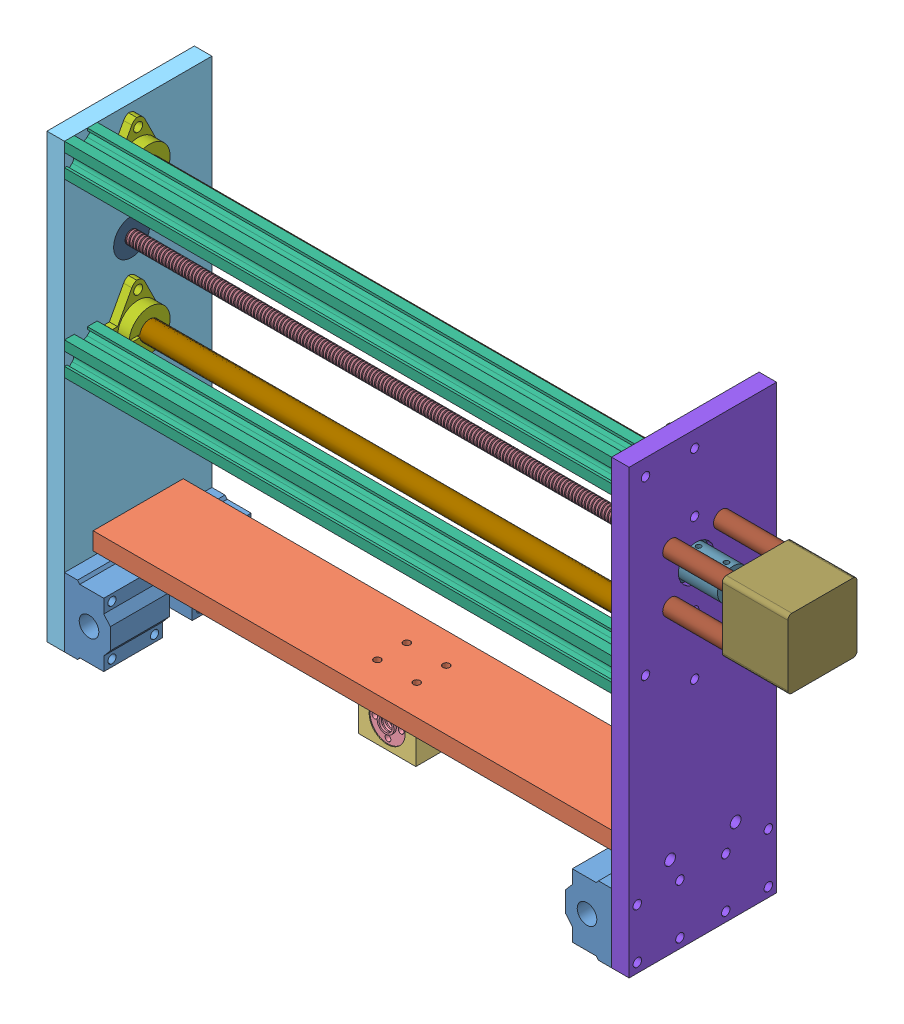
SolidWorks assembly MaquinaEixoX, configuration Valor predeterminado. Lengths in mm.
Overall size (432.4 270 90).
26 component instances, 14 part files, 65 mates.
Components (placement in the parent):
- PillowBlockSCS12UU_12mm-1: PillowBlockSCS12UU_12mm [Valor predeterminado] at (166.1121 14.2573 262.986) x (0 -1 0) z (0 0 1) size (42 28 36)
- PillowBlockSCS12UU_12mm-2: PillowBlockSCS12UU_12mm [Valor predeterminado] at (166.1121 14.2573 352.986) x (0 1 0) z (0 0 -1) size (42 28 36)
- PillowBlockSCS12UU_12mm-3: PillowBlockSCS12UU_12mm [Valor predeterminado] at (-123.9122 14.2573 316.986) x (0 1 0) z (0 0 1) size (42 28 36)
- PillowBlockSCS12UU_12mm-4: PillowBlockSCS12UU_12mm [Valor predeterminado] at (-123.9122 14.2573 262.986) x (0 1 0) z (0 0 1) size (42 28 36)
- EixoYChapaBase-1: EixoYChapaBase [Valor predeterminado] at (188.0999 43.2573 307.986) x (0 0 1) z (-1 0 0) size (55 10.7 334)
- SuporteCastanhaTr8-1: SuporteCastanhaTr8 [Valor predeterminado] at (21.0999 23.9073 292.986) size (35 28 30)
- CastanhaTr8_2mm-1: CastanhaTr8_2mm [Valor predeterminado] at (21.0999 23.9073 318.986) x (0 -1 0) z (0 0 1) size (22 22 15.4)
- ChapaColunaDireita-1: ChapaColunaDireita [Valor predeterminado] at (-145.9001 128.2573 307.986) x (0 0 1) z (-1 0 0) size (90 270 10.7)
- EixoXPerfil20x20mm-2: EixoXPerfil20x20mm [Valor predeterminado] at (-145.9001 148.2573 342.986) x (0 0 -1) z (1 0 0) size (20 20 334)
- EixoXPerfil20x20mm-3: EixoXPerfil20x20mm [Valor predeterminado] at (-145.9001 253.2573 342.986) x (0 0 -1) z (1 0 0) size (20 20 334)
- SuporteGuiaLinear12mm-6: SuporteGuiaLinear12mm [Valor predeterminado] at (-145.9001 235.2573 312.986) x (0 -1 0) z (1 0 0) size (47 28.17 12)
- SuporteGuiaLinear12mm-7: SuporteGuiaLinear12mm [Valor predeterminado] at (-145.9001 149.2573 312.986) x (0 -1 0) z (1 0 0) size (47 28.17 12)
- ChapaColunaEsquerda-1: ChapaColunaEsquerda [Valor predeterminado] at (198.7999 128.2573 307.986) x (0 0 1) z (-1 0 0) size (90 270 10.7)
- SuporteGuiaLinear12mm-8: SuporteGuiaLinear12mm [Valor predeterminado] at (188.0999 235.2573 312.986) x (0 1 0) z (-1 0 0) size (47 28.17 12)
- SuporteGuiaLinear12mm-9: SuporteGuiaLinear12mm [Valor predeterminado] at (188.0999 149.2573 312.986) x (0 1 0) z (-1 0 0) size (47 28.17 12)
- EixoXHasteLinear12mm-1: EixoXHasteLinear12mm [Valor predeterminado] at (188.0999 235.2573 312.986) x (0 0.999795 -0.02023) z (-1 0 0) size (12 12 334)
- EixoXHasteLinear12mm-2: EixoXHasteLinear12mm [Valor predeterminado] at (188.0999 149.2573 312.986) x (0 0.812875 -0.582438) z (-1 0 0) size (12 12 334)
- Rolamento608zz_8mm-3: Rolamento608zz_8mm [Valor predeterminado] at (-152.9001 192.2573 311.986) x (0 -0.289624 -0.95714) z (1 0 0) size (22 22 7)
- Rolamento608zz_8mm-4: Rolamento608zz_8mm [Valor predeterminado] at (188.0999 192.2573 311.986) x (0 0 -1) z (1 0 0) size (22 22 7)
- EspaçadorM3_35mm-1: EspaçadorM3_35mm [Valor predeterminado] at (198.7999 207.7573 327.486) x (0 0 -1) z (1 0 0) size (10 10 37)
- EspaçadorM3_35mm-2: EspaçadorM3_35mm [Valor predeterminado] at (198.7999 176.7573 327.486) x (0 0 -1) z (1 0 0) size (10 10 37)
- EspaçadorM3_35mm-3: EspaçadorM3_35mm [Valor predeterminado] at (198.7999 207.7573 296.486) x (0 0 -1) z (1 0 0) size (10 10 37)
- EspaçadorM3_35mm-4: EspaçadorM3_35mm [Valor predeterminado] at (198.7999 176.7573 296.486) x (0 0 -1) z (1 0 0) size (10 10 37)
- MotorNema17_3.5Kgfcm-1: MotorNema17_3.5Kgfcm [Valor predeterminado] at (275.7999 192.2573 311.986) x (0 0 1) z (-1 0 0) size (42.3 42.3 66)
- EixoXFusoTr8_2mm-1: EixoXFusoTr8_2mm [Valor predeterminado] at (-152.9001 192.2573 311.986) x (0 0 -1) z (1 0 0) size (8.21 9.24 364.96)
- AcoplamentoFlexível5x8mm-1: AcoplamentoFlexível5x8mm [Valor predeterminado] at (221.2588 192.2573 311.986) x (0 0 1) z (-1 0 0) size (19 19 25)
Mates (geometry in assembly coordinates):
- Coincidente277: coincident anti-aligned: plane of EixoYChapaBase-1 through (-145.9001 37.9073 335.486) normal (0 -1 0); plane of SuporteCastanhaTr8-1 through (38.5999 37.9073 322.986) normal (0 1 0)
- Concêntrico161: concentric anti-aligned: circle of EixoYChapaBase-1; circle of SuporteCastanhaTr8-1
- Concêntrico162: concentric anti-aligned: circle of EixoYChapaBase-1; circle of SuporteCastanhaTr8-1
- Coincidente278: coincident anti-aligned: plane of EixoYChapaBase-1 through (-145.9001 43.2573 307.986) normal (-1 0 0); plane of ChapaColunaDireita-1 through (-145.9001 128.2573 307.986) normal (1 0 0)
- Coincidente279: coincident anti-aligned: plane of EixoYChapaBase-1 through (188.0999 43.2573 307.986) normal (1 0 0); plane of ChapaColunaEsquerda-1 through (188.0999 128.2573 307.986) normal (-1 0 0)
- Concêntrico163: concentric aligned: circle of EixoYChapaBase-1; circle of ChapaColunaEsquerda-1
- Concêntrico164: concentric anti-aligned: circle of EixoYChapaBase-1; circle of ChapaColunaDireita-1
- Concêntrico165: concentric anti-aligned: circle of EixoYChapaBase-1; circle of ChapaColunaDireita-1
- Concêntrico166: concentric aligned: circle of EixoYChapaBase-1; circle of ChapaColunaEsquerda-1
- Concêntrico167: concentric anti-aligned: circle of PillowBlockSCS12UU_12mm-1; circle of ChapaColunaEsquerda-1
- Concêntrico173: concentric anti-aligned: circle of PillowBlockSCS12UU_12mm-2; circle of ChapaColunaEsquerda-1
- Concêntrico174: concentric anti-aligned: circle of PillowBlockSCS12UU_12mm-2; circle of ChapaColunaEsquerda-1
- Coincidente285: coincident anti-aligned: plane of PillowBlockSCS12UU_12mm-2 through (188.0999 -6.7427 316.986) normal (1 0 0); plane of ChapaColunaEsquerda-1 through (188.0999 128.2573 307.986) normal (-1 0 0)
- Concêntrico175: concentric anti-aligned: circle of PillowBlockSCS12UU_12mm-1; circle of ChapaColunaEsquerda-1
- Concêntrico176: concentric anti-aligned: circle of PillowBlockSCS12UU_12mm-1; circle of ChapaColunaEsquerda-1
- Coincidente286: coincident anti-aligned: plane of PillowBlockSCS12UU_12mm-1 through (188.0999 35.2573 298.986) normal (1 0 0); plane of ChapaColunaEsquerda-1 through (188.0999 128.2573 307.986) normal (-1 0 0)
- Coincidente287: coincident anti-aligned: plane of PillowBlockSCS12UU_12mm-3 through (-145.9001 -6.7427 352.986) normal (-1 0 0); plane of ChapaColunaDireita-1 through (-145.9001 128.2573 307.986) normal (1 0 0)
- Concêntrico180: concentric aligned: circle of PillowBlockSCS12UU_12mm-3; circle of ChapaColunaDireita-1
- Coincidente288: coincident anti-aligned: plane of PillowBlockSCS12UU_12mm-4 through (-145.9001 -6.7427 298.986) normal (-1 0 0); plane of ChapaColunaDireita-1 through (-145.9001 128.2573 307.986) normal (1 0 0)
- Concêntrico183: concentric aligned: circle of PillowBlockSCS12UU_12mm-4; circle of ChapaColunaDireita-1
- Concêntrico185: concentric aligned: circle of PillowBlockSCS12UU_12mm-4; circle of ChapaColunaDireita-1
- Concêntrico186: concentric aligned: circle of PillowBlockSCS12UU_12mm-3; circle of ChapaColunaDireita-1
- Concêntrico187: concentric aligned: cylinder of SuporteCastanhaTr8-1 through (21.0999 23.9073 292.986) axis (0 0 1) radius 5.15; cylinder of CastanhaTr8_2mm-1 through (21.0999 23.9073 308.986) axis (0 0 1) radius 5.1
- Concêntrico188: concentric aligned: circle of SuporteCastanhaTr8-1; circle of CastanhaTr8_2mm-1
- Coincidente289: coincident anti-aligned: plane of SuporteCastanhaTr8-1 through (21.0999 23.9073 318.986) normal (0 0 1); plane of CastanhaTr8_2mm-1 through (21.0999 23.9073 318.986) normal (0 0 -1)
- Coincidente292: coincident anti-aligned: plane of ChapaColunaDireita-1 through (-152.9001 192.2573 311.986) normal (1 0 0); plane of Rolamento608zz_8mm-3 through (-152.9001 192.2573 311.986) normal (-1 0 0)
- Concêntrico193: concentric anti-aligned: cylinder of ChapaColunaDireita-1 through (-152.9001 192.2573 311.986) axis (1 0 0) radius 11; cylinder of Rolamento608zz_8mm-3 through (-145.9001 192.2573 311.986) axis (-1 0 0) radius 11
- Concêntrico198: concentric anti-aligned: cylinder of ChapaColunaEsquerda-1 through (188.0999 192.2573 311.986) axis (1 0 0) radius 11; cylinder of Rolamento608zz_8mm-4 through (195.0999 192.2573 311.986) axis (-1 0 0) radius 11
- Coincidente295: coincident aligned: plane of ChapaColunaEsquerda-1 through (188.0999 128.2573 307.986) normal (-1 0 0); plane of Rolamento608zz_8mm-4 through (188.0999 192.2573 311.986) normal (-1 0 0)
- Concêntrico203: concentric anti-aligned: cylinder of Rolamento608zz_8mm-3 through (-152.9001 192.2573 311.986) axis (1 0 0) radius 4; cylinder of EixoXFusoTr8_2mm-1 through (207.0999 192.2573 311.986) axis (-1 0 0) radius 4
- Coincidente299: coincident anti-aligned: plane of ChapaColunaDireita-1 through (-152.9001 192.2573 311.986) normal (1 0 0); plane of EixoXFusoTr8_2mm-1 through (-152.9001 192.2573 311.986) normal (-1 0 0)
- Concêntrico204: concentric anti-aligned: circle of EspaçadorM3_35mm-1; circle of MotorNema17_3.5Kgfcm-1
- Coincidente300: coincident anti-aligned: plane of EspaçadorM3_35mm-1 through (235.7999 207.7573 327.486) normal (1 0 0); plane of MotorNema17_3.5Kgfcm-1 through (235.7999 192.2573 311.986) normal (-1 0 0)
- Concêntrico205: concentric anti-aligned: circle of EspaçadorM3_35mm-2; circle of MotorNema17_3.5Kgfcm-1
- Coincidente301: coincident anti-aligned: plane of EspaçadorM3_35mm-2 through (235.7999 176.7573 327.486) normal (1 0 0); plane of MotorNema17_3.5Kgfcm-1 through (235.7999 192.2573 311.986) normal (-1 0 0)
- Concêntrico206: concentric anti-aligned: circle of EspaçadorM3_35mm-4; circle of MotorNema17_3.5Kgfcm-1
- Coincidente302: coincident anti-aligned: plane of EspaçadorM3_35mm-4 through (235.7999 176.7573 296.486) normal (1 0 0); plane of MotorNema17_3.5Kgfcm-1 through (235.7999 192.2573 311.986) normal (-1 0 0)
- Concêntrico207: concentric anti-aligned: circle of EspaçadorM3_35mm-3; circle of MotorNema17_3.5Kgfcm-1
- Coincidente303: coincident anti-aligned: plane of EspaçadorM3_35mm-3 through (235.7999 207.7573 296.486) normal (1 0 0); plane of MotorNema17_3.5Kgfcm-1 through (235.7999 192.2573 311.986) normal (-1 0 0)
- Coincidente304: coincident anti-aligned: plane of ChapaColunaEsquerda-1 through (198.7999 128.2573 307.986) normal (1 0 0); plane of EspaçadorM3_35mm-1 through (198.7999 207.7573 327.486) normal (-1 0 0)
- Concêntrico208: concentric aligned: circle of ChapaColunaEsquerda-1; circle of EspaçadorM3_35mm-1
- Concêntrico209: concentric aligned: circle of ChapaColunaEsquerda-1; circle of EspaçadorM3_35mm-4
- Coincidente305: coincident anti-aligned: plane of EixoXPerfil20x20mm-3 through (188.0999 253.2573 342.986) normal (1 0 0); plane of ChapaColunaEsquerda-1 through (188.0999 128.2573 307.986) normal (-1 0 0)
- Concêntrico210: concentric anti-aligned: circle of EixoXPerfil20x20mm-3; circle of ChapaColunaEsquerda-1
- Concêntrico211: concentric aligned: circle of ChapaColunaDireita-1; circle of EixoXPerfil20x20mm-3
- Coincidente306: coincident anti-aligned: plane of ChapaColunaDireita-1 through (-145.9001 128.2573 307.986) normal (1 0 0); plane of EixoXPerfil20x20mm-2 through (-145.9001 148.2573 342.986) normal (-1 0 0)
- Concêntrico212: concentric aligned: circle of ChapaColunaDireita-1; circle of EixoXPerfil20x20mm-2
- Concêntrico213: concentric anti-aligned: circle of EixoXPerfil20x20mm-2; circle of ChapaColunaEsquerda-1
- Concêntrico214: concentric aligned: cylinder of MotorNema17_3.5Kgfcm-1 through (209.7999 192.2573 311.986) axis (1 0 0) radius 2.5; cylinder of AcoplamentoFlexível5x8mm-1 through (196.2588 192.2573 311.986) axis (1 0 0) radius 2.5
- Coincidente307: coincident anti-aligned: plane of ChapaColunaEsquerda-1 through (188.0999 128.2573 307.986) normal (-1 0 0); plane of SuporteGuiaLinear12mm-8 through (188.0999 235.2573 312.986) normal (1 0 0)
- Concêntrico215: concentric anti-aligned: circle of ChapaColunaEsquerda-1; circle of SuporteGuiaLinear12mm-8
- Concêntrico216: concentric anti-aligned: circle of ChapaColunaEsquerda-1; circle of SuporteGuiaLinear12mm-8
- Coincidente308: coincident anti-aligned: plane of ChapaColunaEsquerda-1 through (188.0999 128.2573 307.986) normal (-1 0 0); plane of SuporteGuiaLinear12mm-9 through (188.0999 149.2573 312.986) normal (1 0 0)
- Concêntrico217: concentric anti-aligned: circle of ChapaColunaEsquerda-1; circle of SuporteGuiaLinear12mm-9
- Concêntrico218: concentric anti-aligned: circle of ChapaColunaEsquerda-1; circle of SuporteGuiaLinear12mm-9
- Coincidente309: coincident anti-aligned: plane of ChapaColunaDireita-1 through (-145.9001 128.2573 307.986) normal (1 0 0); plane of SuporteGuiaLinear12mm-6 through (-145.9001 235.2573 312.986) normal (-1 0 0)
- Concêntrico219: concentric aligned: circle of ChapaColunaDireita-1; circle of SuporteGuiaLinear12mm-6
- Concêntrico220: concentric aligned: circle of ChapaColunaDireita-1; circle of SuporteGuiaLinear12mm-6
- Coincidente310: coincident anti-aligned: plane of ChapaColunaDireita-1 through (-145.9001 128.2573 307.986) normal (1 0 0); plane of SuporteGuiaLinear12mm-7 through (-145.9001 149.2573 312.986) normal (-1 0 0)
- Concêntrico221: concentric aligned: circle of ChapaColunaDireita-1; circle of SuporteGuiaLinear12mm-7
- Concêntrico222: concentric aligned: circle of ChapaColunaDireita-1; circle of SuporteGuiaLinear12mm-7
- Concêntrico223: concentric anti-aligned: cylinder of SuporteGuiaLinear12mm-8 through (188.0999 235.2573 312.986) axis (-1 0 0) radius 6; cylinder of EixoXHasteLinear12mm-1 through (-145.9001 235.2573 312.986) axis (1 0 0) radius 6
- Coincidente311: coincident anti-aligned: plane of ChapaColunaDireita-1 through (-145.9001 128.2573 307.986) normal (1 0 0); plane of EixoXHasteLinear12mm-1 through (-145.9001 235.2573 312.986) normal (-1 0 0)
- Concêntrico224: concentric aligned: cylinder of SuporteGuiaLinear12mm-7 through (-145.9001 149.2573 312.986) axis (1 0 0) radius 6; cylinder of EixoXHasteLinear12mm-2 through (-145.9001 149.2573 312.986) axis (1 0 0) radius 6
- Coincidente312: coincident anti-aligned: plane of ChapaColunaEsquerda-1 through (188.0999 128.2573 307.986) normal (-1 0 0); plane of EixoXHasteLinear12mm-2 through (188.0999 149.2573 312.986) normal (1 0 0)
